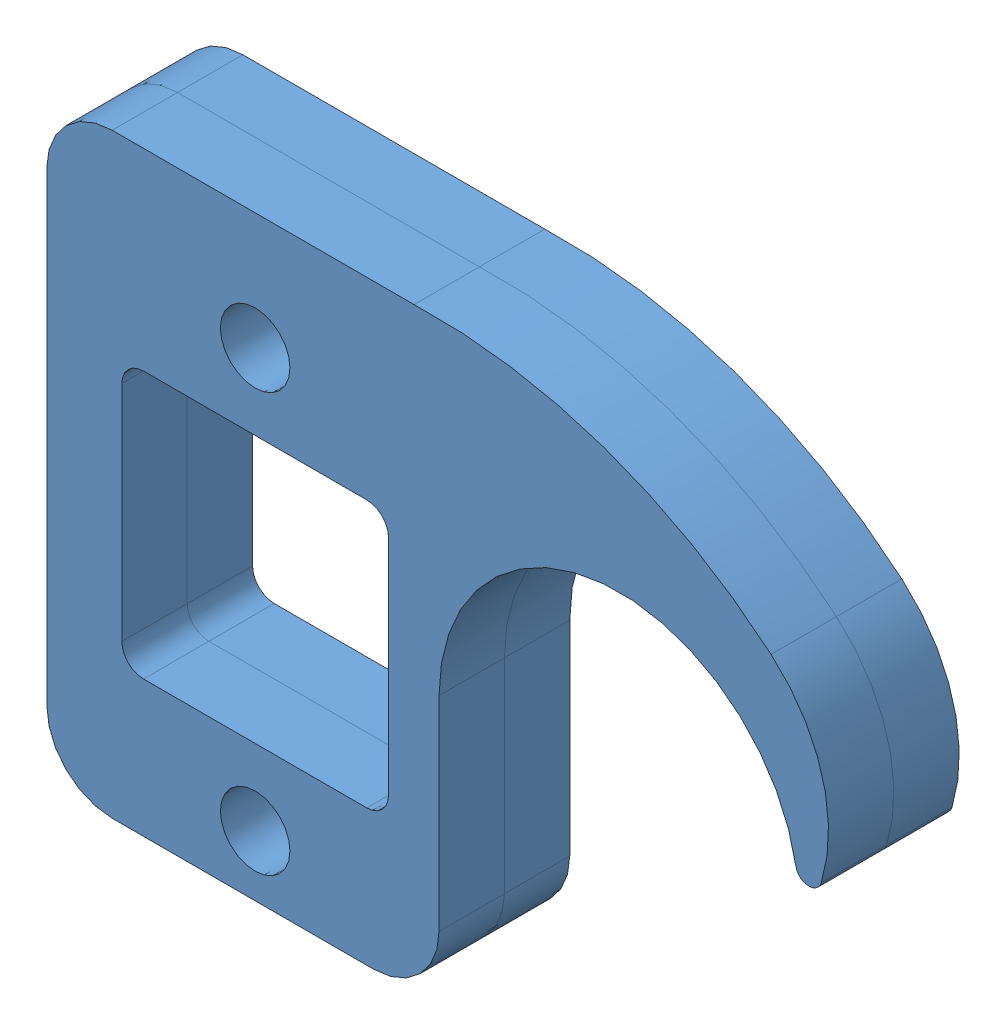
SolidWorks assembly 2018-508-A, configuration Default. Lengths in mm.
Overall size (75.94 57.91 12.7).
2 component instances, 1 part files, 4 mates.
Components (placement in the parent):
- 2018-508-D001-1: 2018-508-D001 [Default] at origin size (75.94 57.91 6.35)
- 2018-508-D001-2: 2018-508-D001 [Default] at (0 0 6.35) size (75.94 57.91 6.35)
Mates (geometry in assembly coordinates):
- Coincident1: coordinate: point of 2018-508-D001-1; point of assembly
- Coincident2: coincident: plane of 2018-508-D001-1 through (-18.1389 -19.0842 3.175) normal (0 0 1); plane of 2018-508-D001-2 through (-18.1389 -19.0842 3.175) normal (0 0 -1)
- Concentric1: concentric: cylinder of 2018-508-D001-1 through (-35.3219 20.32 3.175) axis (0 0 -1) radius 3.3782; cylinder of 2018-508-D001-2 through (-35.3219 20.32 9.525) axis (0 0 -1) radius 3.3782
- Concentric2: concentric aligned: cylinder of 2018-508-D001-1 through (-35.3219 -20.32 3.175) axis (0 0 -1) radius 3.3782; cylinder of 2018-508-D001-2 through (-35.3219 -20.32 9.525) axis (0 0 -1) radius 3.3782
